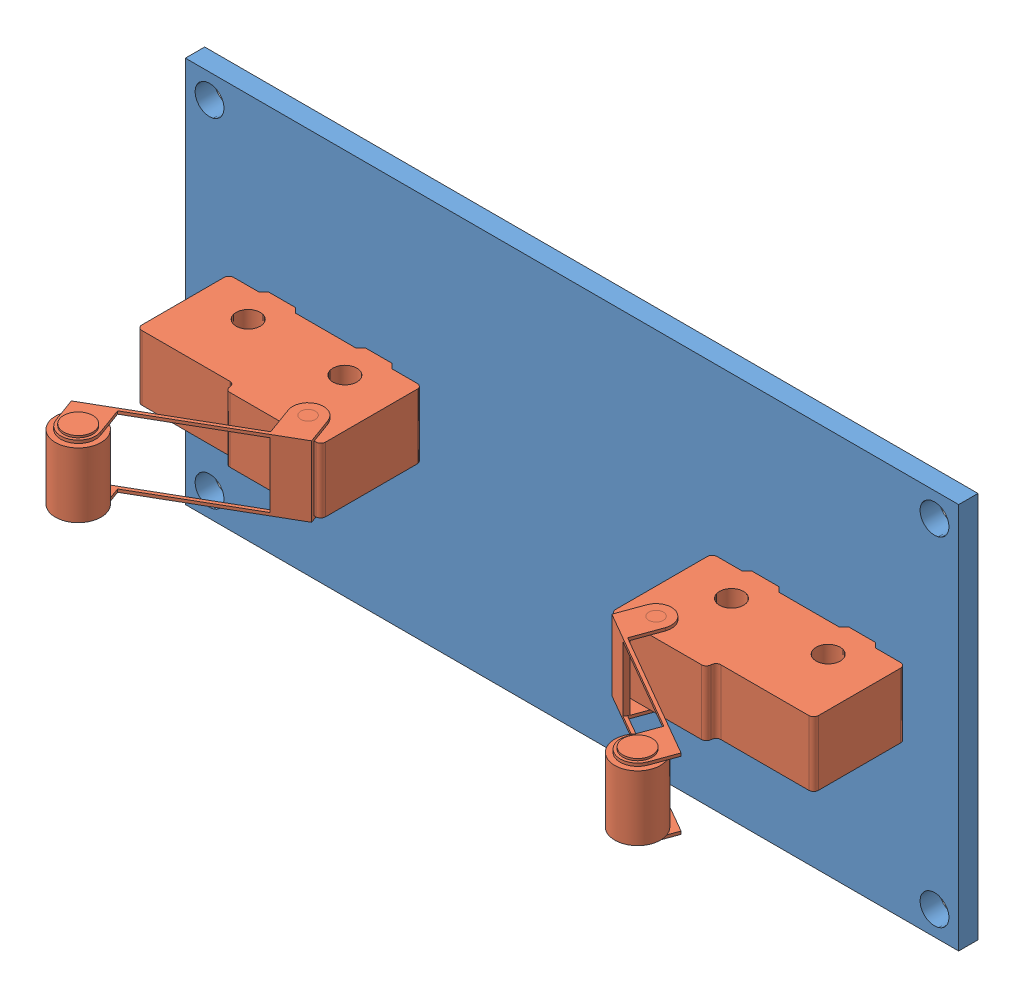
SolidWorks assembly pcb_bumper, configuration Défaut. Lengths in mm.
Overall size (80 40 28.01).
3 component instances, 2 part files, 6 mates.
Components (placement in the parent):
- pcb_interrupteur-1: pcb_interrupteur [Défaut] at (-32.9434 -18.8522 80) size (80 40 2)
- microswitch-1: microswitch [Défaut] at (-7.9434 4.4978 82.5) x (1 0 0) z (0 -1 0) size (20 28.01 7.7)
- microswitch-2: microswitch [Défaut] at (22.0566 -2.2022 82.5) x (-1 0 0) z (0 1 0) size (20 28.01 7.7)
Mates (geometry in assembly coordinates):
- Coïncidente1: coincident anti-aligned: plane of pcb_interrupteur-1 through (-32.9434 -18.8522 82) normal (0 0 1); plane of microswitch-2 through (38.4566 -2.2022 82) normal (0 0 -1)
- Coïncidente2: coincident anti-aligned: plane of pcb_interrupteur-1 through (-32.9434 -18.8522 82) normal (0 0 1); plane of microswitch-1 through (-14.3434 4.4978 82) normal (0 0 -1)
- Distance1: distance = 30 mm anti-aligned: plane of microswitch-2 through (22.0566 -2.2022 82.5) normal (-1 0 0); plane of microswitch-1 through (-7.9434 4.4978 82.5) normal (1 0 0)
- Distance2: distance = 16.65 mm aligned: plane of microswitch-1 through (-17.9434 4.4978 87.25) normal (0 1 0); plane of pcb_interrupteur-1 through (-32.9434 21.1478 82) normal (0 1 0)
- Distance3: distance = 16.65 mm aligned: plane of microswitch-2 through (32.0566 4.4978 87.25) normal (0 1 0); plane of pcb_interrupteur-1 through (-32.9434 21.1478 82) normal (0 1 0)
- Distance4: distance = 5 mm aligned: plane of microswitch-2 through (42.0566 -2.2022 92) normal (1 0 0); plane of pcb_interrupteur-1 through (47.0566 -18.8522 82) normal (1 0 0)
